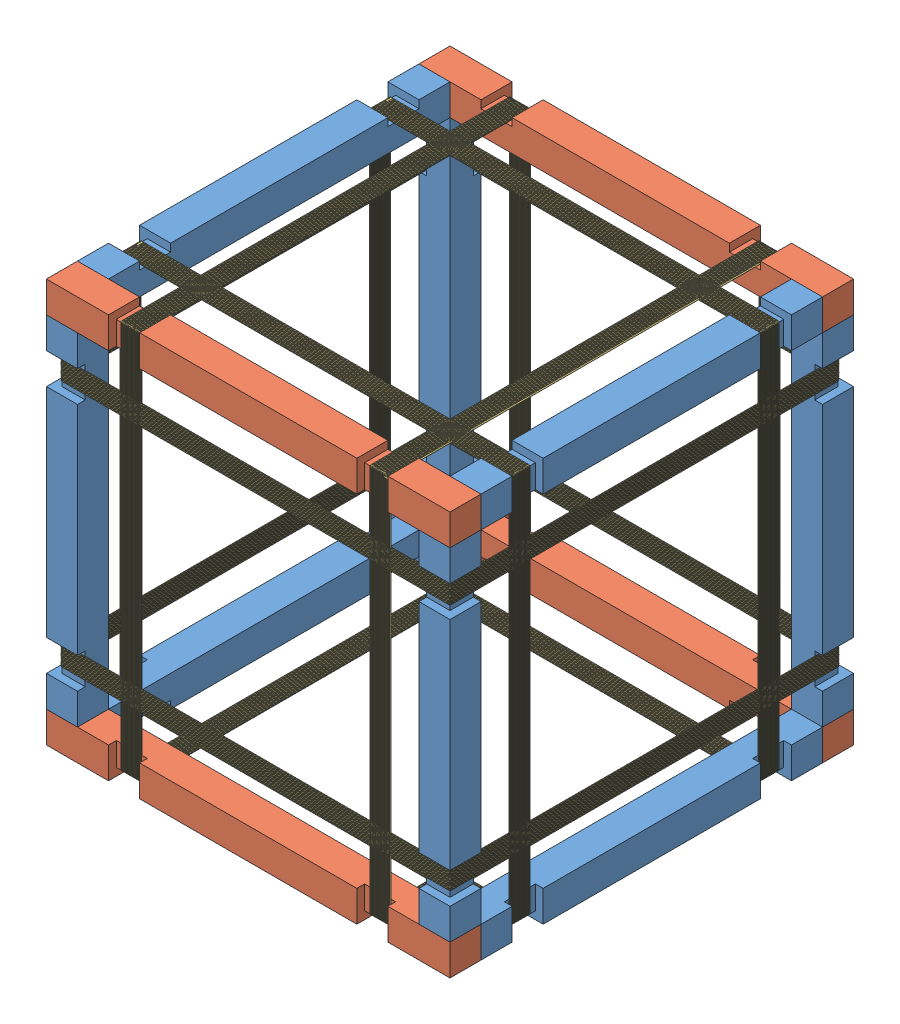
SolidWorks assembly HemCage, configuration Default. Lengths in mm.
Overall size (660.4 660.4 660.4).
18 component instances, 3 part files, 34 mates.
Components (placement in the parent):
- 2x2x22-1: 2x2x22 [Default] at (-304.8 0 -279.4) x (-1 0 0) z (0 0 -1) size (50.8 558.8 50.8)
- 2x2x26-1: 2x2x26 [Default] at (0 279.4 -304.8) x (0 0 -1) z (0 1 0) size (50.8 660.4 50.8)
- 2x2x26-2: 2x2x26 [Default] at (0 -304.8 -279.4) x (0 -1 0) z (0 0 -1) size (50.8 660.4 50.8)
- 2x2x22-2: 2x2x22 [Default] at (279.4 0 -304.8) x (0 0 -1) z (1 0 0) size (50.8 558.8 50.8)
- 2x2x22-3: 2x2x22 [Default] at (304.8 279.4 0) x (1 0 0) z (0 1 0) size (50.8 558.8 50.8)
- 2x2x22-4: 2x2x22 [Default] at (-279.4 304.8 0) x (0 1 0) z (-1 0 0) size (50.8 558.8 50.8)
- 2x2x22-5: 2x2x22 [Default] at (-304.8 -279.4 0) x (-1 0 0) z (0 -1 0) size (50.8 558.8 50.8)
- 2x2x22-6: 2x2x22 [Default] at (279.4 -304.8 0) x (0 -1 0) z (1 0 0) size (50.8 558.8 50.8)
- 2x2x26-3: 2x2x26 [Default] at (0 -304.8 279.4) x (0 -1 0) z (0 0 1) size (50.8 660.4 50.8)
- 2x2x22-7: 2x2x22 [Default] at (-279.4 0 304.8) x (0 0 1) z (-1 0 0) size (50.8 558.8 50.8)
- 2x2x22-8: 2x2x22 [Default] at (304.8 0 279.4) size (50.8 558.8 50.8)
- 2x2x26-5: 2x2x26 [Default] at (0 304.8 279.4) x (0 1 0) z (0 0 1) size (50.8 660.4 50.8)
- HelmholtzWire-1: HelmholtzWire [Default] at (317.5 0.5 192.7) x (1 0 0) z (0 -1 0) size (638 33.5 638)
- HelmholtzWire-2: HelmholtzWire [Default] at (317.5 0.5 -215.2) x (1 0 0) z (0 -1 0) size (638 33.5 638)
- HelmholtzWire-3: HelmholtzWire [Default] at (317.5 -213.7 -0.5) size (638 33.5 638)
- HelmholtzWire-4: HelmholtzWire [Default] at (317.5 191.2 -0.5) size (638 33.5 638)
- HelmholtzWire-5: HelmholtzWire [Default] at (-215.2 -317.5 -0.5) x (0 -1 0) z (0 0 1) size (638 33.5 638)
- HelmholtzWire-6: HelmholtzWire [Default] at (215.2 -317.5 -0.5) x (0 -1 0) z (0 0 -1) size (638 33.5 638)
Mates (geometry in assembly coordinates):
- Concentric1: concentric anti-aligned: circle of 2x2x22-1; circle of 2x2x26-1
- Coincident2: coincident aligned: line of 2x2x22-1 through (-330.2 279.4 -330.2) axis (0 0 1); line of 2x2x26-1 through (-330.2 279.4 -330.2) axis (0 0 1)
- Concentric2: concentric anti-aligned: circle of 2x2x22-1; circle of 2x2x26-2
- Coincident4: coincident aligned: line of 2x2x22-1 through (-330.2 -279.4 -330.2) axis (0 0 1); line of 2x2x26-2 through (-330.2 -279.4 -330.2) axis (0 0 1)
- Concentric3: concentric anti-aligned: circle of 2x2x26-2; circle of 2x2x22-2
- Coincident6: coincident anti-aligned: line of 2x2x26-2 through (330.2 -279.4 -330.2) axis (0 0 1); line of 2x2x22-2 through (330.2 -279.4 -279.4) axis (0 0 -1)
- Concentric4: concentric anti-aligned: circle of 2x2x26-1; circle of 2x2x22-3
- Coincident9: coincident anti-aligned: line of 2x2x26-1 through (228.6 330.2 -279.4) axis (1 0 0); line of 2x2x22-3 through (330.2 330.2 -279.4) axis (-1 0 0)
- Concentric5: concentric anti-aligned: circle of 2x2x26-1; circle of 2x2x22-4
- Coincident11: coincident aligned: line of 2x2x26-1 through (-330.2 279.4 -279.4) axis (1 0 0); line of 2x2x22-4 through (-330.2 279.4 -279.4) axis (1 0 0)
- Concentric6: concentric anti-aligned: circle of 2x2x26-2; circle of 2x2x22-5
- Coincident13: coincident aligned: line of 2x2x26-2 through (-330.2 -279.4 -279.4) axis (1 0 0); line of 2x2x22-5 through (-330.2 -279.4 -279.4) axis (1 0 0)
- Concentric7: concentric anti-aligned: circle of 2x2x26-2; circle of 2x2x22-6
- Coincident15: coincident aligned: line of 2x2x26-2 through (330.2 -330.2 -279.4) axis (-1 0 0); line of 2x2x22-6 through (330.2 -330.2 -279.4) axis (-1 0 0)
- Concentric8: concentric anti-aligned: circle of 2x2x22-5; circle of 2x2x26-3
- Coincident17: coincident anti-aligned: line of 2x2x22-5 through (-330.2 -330.2 279.4) axis (0 1 0); line of 2x2x26-3 through (-330.2 -279.4 279.4) axis (0 -1 0)
- Concentric10: concentric aligned: circle of 2x2x26-3; circle of 2x2x22-7
- Coincident23: coincident anti-aligned: line of 2x2x26-3 through (-330.2 -279.4 330.2) axis (0 0 -1); line of 2x2x22-7 through (-330.2 -279.4 279.4) axis (0 0 1)
- Concentric11: concentric anti-aligned: circle of 2x2x26-3; circle of 2x2x22-8
- Coincident26: coincident anti-aligned: line of 2x2x26-3 through (330.2 -279.4 330.2) axis (-1 0 0); line of 2x2x22-8 through (279.4 -279.4 330.2) axis (1 0 0)
- Concentric12: concentric anti-aligned: circle of 2x2x22-7; circle of 2x2x26-5
- Coincident28: coincident aligned: line of 2x2x22-7 through (-330.2 279.4 330.2) axis (0 0 -1); line of 2x2x26-5 through (-330.2 279.4 330.2) axis (0 0 -1)
- Coincident29: coincident anti-aligned: plane of 2x2x22-3 through (304.8 279.4 0) normal (0 0 -1)
- Coincident30: coincident aligned: plane of 2x2x22-2 through (279.4 0 -304.8) normal (0 1 0)
- Coincident32: coincident anti-aligned: plane of 2x2x26-1 through (0 279.4 -304.8) normal (-1 0 0)
- Coincident34: coincident anti-aligned: plane of 2x2x22-4 through (-279.4 317.5 0) normal (0 1 0); plane of HelmholtzWire-1 through (-316.5 317.5 197.7) normal (0 -1 0)
- Coincident35: coincident anti-aligned: plane of 2x2x22-4 through (-317.5 304.8 0) normal (-1 0 0); plane of HelmholtzWire-1 through (-317.5 316.5 197.7) normal (1 0 0)
- Width1: width: cylinder of 2x2x22-4; plane of HelmholtzWire-1 through (-317.5 330.2 228.6) normal (0 0 -1); cylinder of 2x2x22-4 through (315.5 318.5 203.2) axis (-1 0 0) radius 1
- Coincident36: coincident anti-aligned: plane of 2x2x22-1 through (-304.8 0 -317.5) normal (0 0 -1); plane of HelmholtzWire-3 through (-316.5 -208.7 -317.5) normal (0 0 1)
- Coincident37: coincident anti-aligned: plane of 2x2x22-1 through (-317.5 0 -279.4) normal (-1 0 0); plane of HelmholtzWire-3 through (-317.5 -208.7 -316.5) normal (1 0 0)
- Width2: width: plane of 2x2x22-1 through (-330.2 -177.8 -317.5) normal (0 -1 0); plane of HelmholtzWire-3 through (-330.2 -228.6 -317.5) normal (0 1 0); cylinder of 2x2x22-1 through (315.5 -203.2 -318.5) axis (-1 0 0) radius 1
- Coincident38: coincident anti-aligned: plane of 2x2x26-1 through (0 279.4 -317.5) normal (0 0 -1); plane of HelmholtzWire-5 through (-210.2 316.5 -317.5) normal (0 0 1)
- Coincident39: coincident anti-aligned: plane of 2x2x26-1 through (0 317.5 -304.8) normal (0 1 0); plane of HelmholtzWire-5 through (-210.2 317.5 -316.5) normal (0 -1 0)
- Width3: width: plane of 2x2x26-1 through (-228.6 317.5 -279.4) normal (1 0 0); plane of HelmholtzWire-5 through (-177.8 317.5 -279.4) normal (-1 0 0); cylinder of 2x2x26-1 through (-203.2 -315.5 -318.5) axis (0 1 0) radius 1
